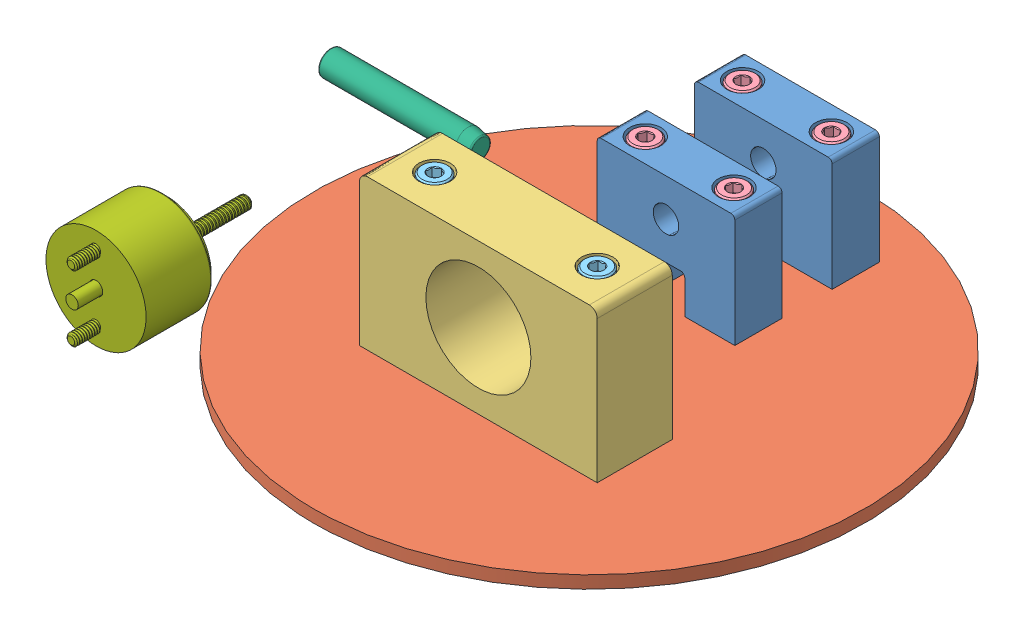
SolidWorks assembly Thesis4_assy.1, configuration Default. Lengths in mm.
Overall size (158.18 41.67 139.7).
12 component instances, 7 part files, 22 mates.
Components (placement in the parent):
- Thesis4_pin_block.1-1: Thesis4_pin_block.1 [Default] at (0 3.175 -31.496) size (34.92 28.57 12)
- Thesis4_pin_block.1-2: Thesis4_pin_block.1 [Default] at (0 3.175 -56.196) size (34.92 28.57 12)
- Thesis4_base_plate-1: Thesis4_base_plate [Default] at origin size (139.7 3.17 139.7)
- Thesis4_solenoid_housing.1-1: Thesis4_solenoid_housing.1 [Default] at (0 3.175 18.604) size (60.32 38.1 19.05)
- 91292A122_TYPE 18-8 SS SOCKET HEAD CAP SCREW-1: 91292A122_TYPE 18-8 SS SOCKET HEAD CAP SCREW [91292A122] at (11.2625 2.75 -25.496) x (0.36243 0 0.932011) z (0 -1 0) size (7 7 29.79)
- 91292A130_TYPE 18-8 SS SOCKET HEAD CAP SCREW-1: 91292A130_TYPE 18-8 SS SOCKET HEAD CAP SCREW [91292A130] at (-20.6375 7.275 18.604) x (1 0 0) z (0 -1 0) size (7 7 34.79)
- 91292A122_TYPE 18-8 SS SOCKET HEAD CAP SCREW-2: 91292A122_TYPE 18-8 SS SOCKET HEAD CAP SCREW [91292A122] at (11.2625 2.75 -50.196) x (-0.881785 0 -0.471651) z (0 -1 0) size (7 7 29.79)
- 91292A122_TYPE 18-8 SS SOCKET HEAD CAP SCREW-3: 91292A122_TYPE 18-8 SS SOCKET HEAD CAP SCREW [91292A122] at (-11.2625 2.75 -25.496) x (0.815547 0 -0.57869) z (0 -1 0) size (7 7 29.79)
- 91292A122_TYPE 18-8 SS SOCKET HEAD CAP SCREW-4: 91292A122_TYPE 18-8 SS SOCKET HEAD CAP SCREW [91292A122] at (-11.2625 2.75 -50.196) x (0.569895 0 -0.821718) z (0 -1 0) size (7 7 29.79)
- 91292A130_TYPE 18-8 SS SOCKET HEAD CAP SCREW-2: 91292A130_TYPE 18-8 SS SOCKET HEAD CAP SCREW [91292A130] at (20.6375 7.275 18.604) x (0.194226 0 0.980957) z (0 -1 0) size (7 7 34.79)
- 97175A318_STANDARD PULL-OUT DOWEL PIN-1: 97175A318_STANDARD PULL-OUT DOWEL PIN [97175A318] at (-68.9793 11.2955 -22.3669) size (38.4 6.35 6.35)
- 6873K110_COMPACT LINEAR SOLENOID-1: 6873K110_COMPACT LINEAR SOLENOID [6873K11] at (-66.9177 12.4751 58.2594) size (25.4 25.4 45.18)
Mates (geometry in assembly coordinates):
- Coincident1: coincident: plane of Thesis4_base_plate-1 through (0 0 0) normal (0 -1 0); plane of assembly through (0 0 0) normal (0 1 0)
- Coincident2: coincident: plane of Thesis4_base_plate-1 through (0 0 0) normal (0 0 1); plane of assembly through (0 0 0) normal (0 0 1)
- Coincident3: coincident: plane of Thesis4_base_plate-1 through (0 0 0) normal (1 0 0); plane of assembly through (0 0 0) normal (1 0 0)
- Coincident4: coincident: plane of Thesis4_pin_block.1-2 through (4.7625 3.175 -44.196) normal (0 -1 0); plane of Thesis4_base_plate-1 through (0 3.175 0) normal (0 1 0)
- Coincident5: coincident: plane of Thesis4_pin_block.1-1 through (-4.7625 3.175 -19.496) normal (0 -1 0); plane of Thesis4_base_plate-1 through (0 3.175 0) normal (0 1 0)
- Concentric1: concentric: cylinder of Thesis4_pin_block.1-1 through (0 22.225 -19.496) axis (0 0 -1) radius 3.2385; cylinder of Thesis4_pin_block.1-2 through (0 22.225 -44.196) axis (0 0 -1) radius 3.2385
- Distance3: distance = 0 mm: plane of assembly through (0 0 0) normal (1 0 0); cylinder of Thesis4_pin_block.1-2 through (0 22.225 -44.196) axis (0 0 -1) radius 3.2385
- Distance4: distance = 44.196 mm: plane of assembly through (0 0 0) normal (0 0 1); plane of Thesis4_pin_block.1-2 through (0 3.175 -44.196) normal (0 0 1)
- Distance5: distance = 12.7 mm: plane of Thesis4_pin_block.1-1 through (0 3.175 -31.496) normal (0 0 -1); plane of Thesis4_pin_block.1-2 through (0 3.175 -44.196) normal (0 0 1)
- Concentric6: concentric: cylinder of Thesis4_solenoid_housing.1-1 through (20.6375 41.275 18.604) axis (0 1 0) radius 4; cylinder of 91292A130_TYPE 18-8 SS SOCKET HEAD CAP SCREW-2 through (20.6375 41.275 18.604) axis (0 -1 0) radius 3.5
- Concentric7: concentric: cylinder of Thesis4_solenoid_housing.1-1 through (-20.6375 41.275 18.604) axis (0 1 0) radius 4; cylinder of 91292A130_TYPE 18-8 SS SOCKET HEAD CAP SCREW-1 through (-20.6375 41.275 18.604) axis (0 -1 0) radius 3.5
- Coincident10: coincident: plane of Thesis4_solenoid_housing.1-1 through (-18.3875 37.275 18.604) normal (0 1 0); plane of 91292A130_TYPE 18-8 SS SOCKET HEAD CAP SCREW-1 through (-20.6375 37.275 18.604) normal (0 -1 0)
- Coincident11: coincident: plane of Thesis4_solenoid_housing.1-1 through (22.8875 37.275 18.604) normal (0 1 0); plane of 91292A130_TYPE 18-8 SS SOCKET HEAD CAP SCREW-2 through (20.6375 37.275 18.604) normal (0 -1 0)
- Concentric8: concentric: cylinder of Thesis4_pin_block.1-1 through (-11.2625 31.75 -25.496) axis (0 1 0) radius 4; cylinder of 91292A122_TYPE 18-8 SS SOCKET HEAD CAP SCREW-3 through (-11.2625 31.75 -25.496) axis (0 -1 0) radius 3.5
- Concentric9: concentric: cylinder of Thesis4_pin_block.1-1 through (11.2625 31.75 -25.496) axis (0 1 0) radius 4; cylinder of 91292A122_TYPE 18-8 SS SOCKET HEAD CAP SCREW-1 through (11.2625 31.75 -25.496) axis (0 -1 0) radius 3.5
- Concentric10: concentric: cylinder of Thesis4_pin_block.1-2 through (-11.2625 31.75 -50.196) axis (0 1 0) radius 4; cylinder of 91292A122_TYPE 18-8 SS SOCKET HEAD CAP SCREW-4 through (-11.2625 31.75 -50.196) axis (0 -1 0) radius 3.5
- Concentric11: concentric: cylinder of Thesis4_pin_block.1-2 through (11.2625 31.75 -50.196) axis (0 1 0) radius 4; cylinder of 91292A122_TYPE 18-8 SS SOCKET HEAD CAP SCREW-2 through (11.2625 31.75 -50.196) axis (0 -1 0) radius 3.5
- Coincident12: coincident: plane of Thesis4_pin_block.1-1 through (-9.0125 27.75 -25.496) normal (0 1 0); plane of 91292A122_TYPE 18-8 SS SOCKET HEAD CAP SCREW-3 through (-11.2625 27.75 -25.496) normal (0 -1 0)
- Coincident13: coincident: plane of Thesis4_pin_block.1-1 through (13.5125 27.75 -25.496) normal (0 1 0); plane of 91292A122_TYPE 18-8 SS SOCKET HEAD CAP SCREW-1 through (11.2625 27.75 -25.496) normal (0 -1 0)
- Coincident14: coincident: plane of Thesis4_pin_block.1-2 through (-9.0125 27.75 -50.196) normal (0 1 0); plane of 91292A122_TYPE 18-8 SS SOCKET HEAD CAP SCREW-4 through (-11.2625 27.75 -50.196) normal (0 -1 0)
- Coincident15: coincident: plane of Thesis4_pin_block.1-2 through (13.5125 27.75 -50.196) normal (0 1 0); plane of 91292A122_TYPE 18-8 SS SOCKET HEAD CAP SCREW-2 through (11.2625 27.75 -50.196) normal (0 -1 0)
- Distance7: distance = 28.575 mm: plane of Thesis4_solenoid_housing.1-1 through (-30.1625 41.275 9.079) normal (0 0 -1); plane of Thesis4_pin_block.1-1 through (0 3.175 -19.496) normal (0 0 1)
